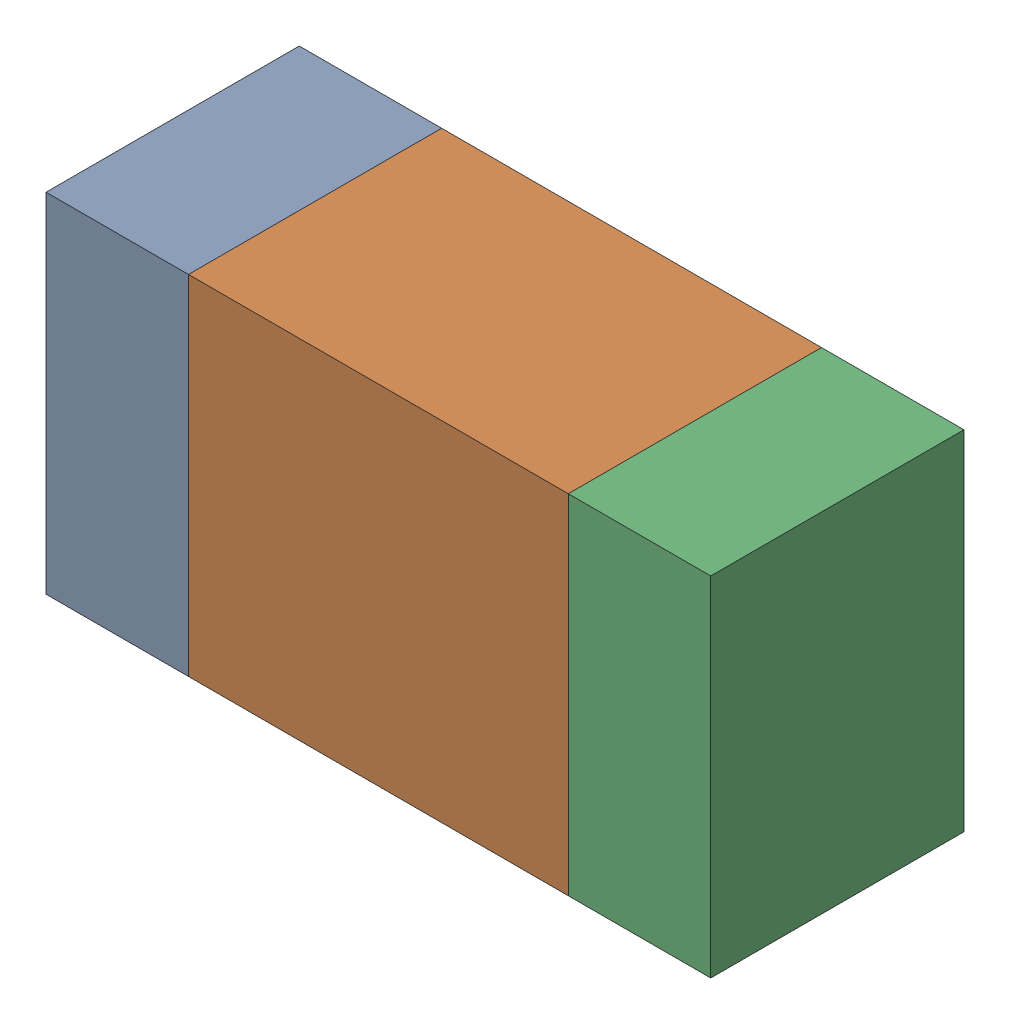
SolidWorks assembly R116_1PCB, configuration Default. Lengths in mm.
Overall size (1.05 0.55 0.4).
6 component instances, 2 part files, 0 mates.
Components (placement in the parent):
- 854785432-1: 854785432 [Default] at (98.8876 116.5001 0) size (0.22 0.55 0.4)
  - Extruded-1: Extruded [Default] at origin size (0.22 0.55 0.4)
- 854785568-1: 854785568 [Default] at (99.3001 116.5001 0) size (0.6 0.55 0.4)
  - Extruded_2-1: Extruded_2 [Default] at origin size (0.6 0.55 0.4)
- 854785432-2: 854785432 [Default] at (99.7126 116.5001 0) size (0.22 0.55 0.4)
  - Extruded-1: Extruded [Default] at origin size (0.22 0.55 0.4)
